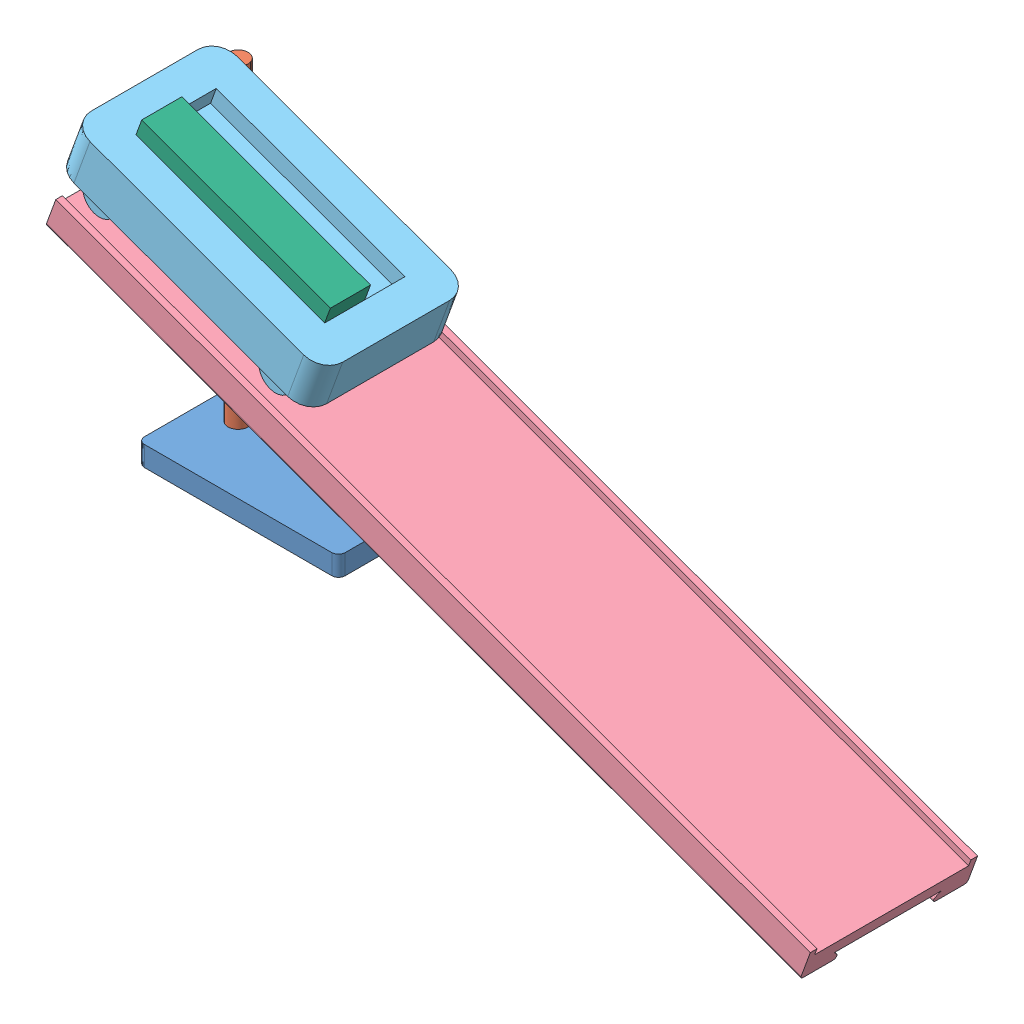
SolidWorks assembly lab™, configuration Default. Lengths in mm.
Overall size (117.75 54.93 37.25).
6 component instances, 6 part files, 16 mates.
Components (placement in the parent):
- base-1: base [Default] at (-8.3978 15.2066 34.7388) size (30 3 20)
- Part3^lab™-1: Part3^lab™ [Default] at (-8.3978 15.2066 34.7388) x (-1 0 0) z (0 -1 0) size (3 3 50) (virtual)
- Part4^lab™-1: Part4^lab™ [Default] at (7.4775 60.5229 27.3324) x (-0.227528 0 -0.973771) z (0 1 0) size (4.5 4.5 4) (virtual)
- Tracc-1: Tracc [Default] at (-3.7402 59.5833 26.9888) x (0.939553 -0.342403 0) z (-0.342403 -0.939553 0) size (120 25 4.5)
- cartt-1: cartt [Default] at (-5.6135 62.9269 49.8778) x (0.939553 -0.342403 0) z (0.342403 0.939553 0) size (40 22 9.5)
- Part8^lab™-1: Part8^lab™ [Default] at (-4.0727 67.1549 49.8778) x (0.939553 -0.342403 0) z (0.342403 0.939553 0) size (30 6 5) (virtual)
Mates (geometry in assembly coordinates):
- InPlace1: in place: plane of base-1 through (-8.3978 15.2066 34.7388) normal (0 -1 0); plane of ? through (0 15.2066 0) normal (0 -1 0); moOrthogonalPlaneRef_w of base-1 through (-8.3978 15.2066 34.7388) normal (0 -1 0); plane of ? through (0 15.2066 0) normal (0 0 -1); plane of base-1 through (-8.3978 15.2066 34.7388) normal (0 -1 0); plane of ? through (0 15.2066 0) normal (-1 0 0); plane of base-1 through (-8.3978 15.2066 34.7388) normal (0 -1 0); unknown of Part3^lab™-1
- Coincident1: coincident: plane of base-1; plane of Part3^lab™-1
- Coincident2: coincident: moOrthogonalPlaneRef_w of base-1 through (-8.3978 15.2066 34.7388) normal (0 0 -1); plane of Part3^lab™-1 through (-8.3978 15.2066 34.7388) normal (0 0 -1)
- Coincident3: coincident: moOrthogonalPlaneRef_w of base-1 through (-8.3978 15.2066 34.7388) normal (1 0 0); plane of Part3^lab™-1 through (-8.3978 15.2066 34.7388) normal (-1 0 0)
- Tangent1: tangent: cylinder of Part4^lab™-1 through (-3.3978 56.5229 24.7388) axis (0 1 0) radius 2.25; plane of Tracc-1 through (-4.9386 56.2949 26.9888) normal (0 0 -1)
- Concentric1: concentric: cylinder of Part3^lab™-1 through (-3.3978 65.2066 24.7388) axis (0 -1 0) radius 1.5; cylinder of Part4^lab™-1 through (-3.3978 56.5229 24.7388) axis (0 1 0) radius 2.25
- Parallel1: parallel: line of base-1 through (21.6022 15.2066 33.7388) axis (0 0 -1); line of Tracc-1 through (107.8078 15.2066 27.4888) axis (0 0 1)
- Coincident8: coincident: plane of base-1 through (-8.3978 15.2066 34.7388) normal (0 -1 0); line of Tracc-1 through (107.8078 15.2066 47.1305) axis (0 0 1)
- Coincident9: coincident: circle of Part4^lab™-1; point of Tracc-1
- Tangent2: tangent: plane of Tracc-1; cylinder of cartt-1 through (26.3313 51.2852 29.8778) axis (0 0 -1) radius 2.5
- Tangent4: tangent: plane of Tracc-1 through (-3.7402 59.5833 26.9888) normal (0.342403 0.939553 0); cylinder of cartt-1 through (0.0238 60.8724 29.8778) axis (0 0 -1) radius 2.5
- Parallel2: parallel: plane of Tracc-1 through (-3.3978 60.5229 50.9888) normal (0 0 -1); plane of cartt-1 through (-3.2167 69.5037 49.8778) normal (0 0 1)
- InPlace3: in place: plane of cartt-1 through (-4.0727 67.1549 49.8778) normal (0.342403 0.939553 0); plane of ? through (21.1266 57.9714 0) normal (0.342403 0.939553 0); plane of cartt-1 through (-4.0727 67.1549 49.8778) normal (0.342403 0.939553 0); plane of ? through (21.1266 57.9714 0) normal (0 0 -1); plane of cartt-1 through (-4.0727 67.1549 49.8778) normal (0.342403 0.939553 0); plane of ? through (21.1266 57.9714 0) normal (0.939553 -0.342403 0); plane of cartt-1 through (-4.0727 67.1549 49.8778) normal (0.342403 0.939553 0); unknown of Part8^lab™-1
- Coincident11: coincident: plane of cartt-1; plane of Part8^lab™-1
- Coincident12: coincident: moOrthogonalPlaneRef_w of cartt-1 through (-4.0727 67.1549 49.8778) normal (0 0 -1); plane of Part8^lab™-1 through (-4.0727 67.1549 49.8778) normal (0 0 -1)
- Coincident13: coincident: moOrthogonalPlaneRef_w of cartt-1 through (-4.0727 67.1549 49.8778) normal (-0.939553 0.342403 0); plane of Part8^lab™-1 through (-4.0727 67.1549 49.8778) normal (0.939553 -0.342403 0)
